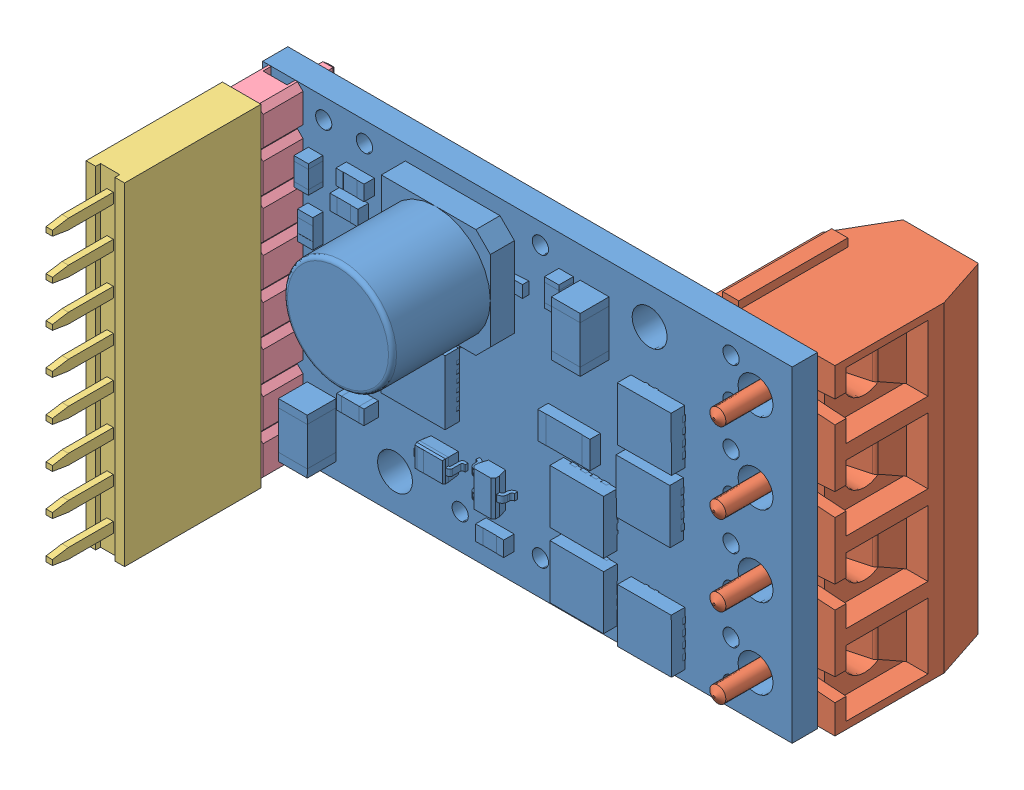
SolidWorks assembly g2-18v17ASM, configuration Default. Lengths in mm.
Overall size (34.11 20.85 26.15).
4 component instances, 4 part files, 0 mates.
Components (placement in the parent):
- g2-high-power-motor-driver-md31a.step-2: g2-high-power-motor-driver-md31a.step [Default] at (-16.5 -10.15 0) size (33.02 20.32 9.57)
- WJ301PRT-1: WJ301PRT [Default] at (14.21 -10 0) x (1 0 0) z (0 1 0) size (7.6 14.15 20.5)
- pin254femalex8-2: pin254femalex8 [Default] at (-16.43 -10.35 12.65) x (0 1 0) z (-1 0 0) size (20.72 12 2.4)
- pin254malex8-1: pin254malex8 [Default] at (-13.98 -10.13 1.57) x (0 1 0) z (1 0 0) size (20.28 11.5 2.5)
